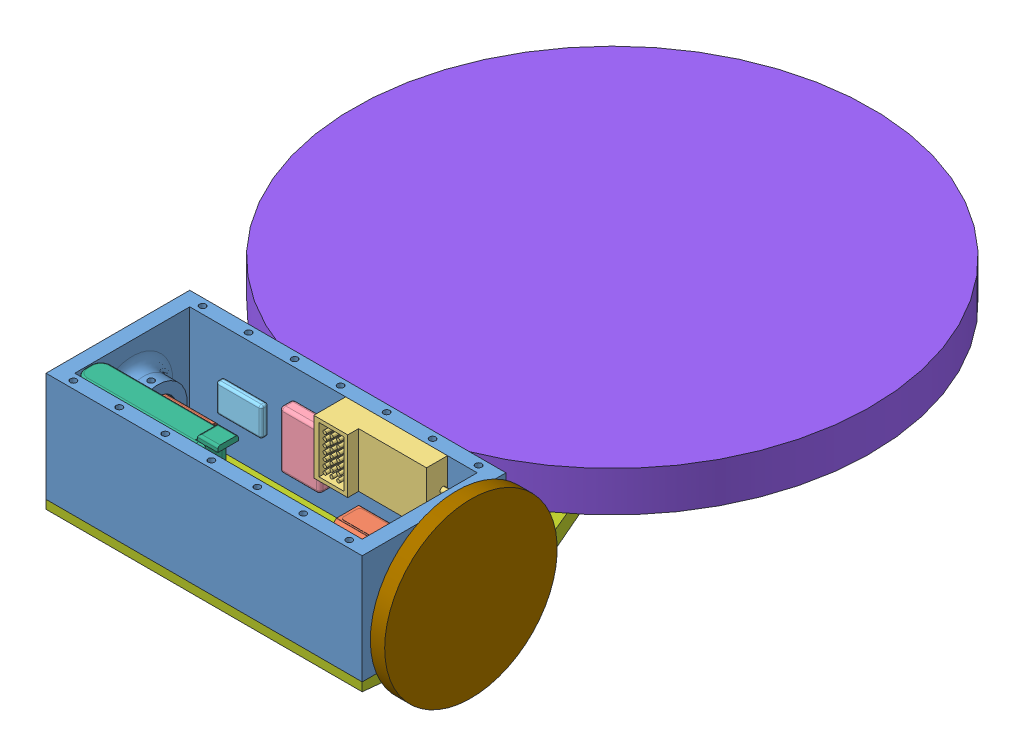
SolidWorks assembly tombstone chassis, configuration Default. Lengths in mm.
Overall size (238.32 80.48 307.99).
11 component instances, 9 part files, 21 mates.
Components (placement in the parent):
- mid chassis-1: mid chassis [Default] at (-76.5443 -11.5001 27.5648) size (144.78 48.26 63.5)
- Brushed Drive Motor-1: Brushed Drive Motor [Default] at (-65.1315 16.4399 -4.1852) x (1 0 0) z (0 -1 0) size (53.82 17.99 16.08)
- Brushed Drive Motor-2: Brushed Drive Motor [Default] at (51.7429 16.4399 -4.1852) x (-1 0 0) z (0 -1 0) size (53.82 17.99 16.08)
- Reciever (1)-1: Reciever (1) [Default] at (-1.286 16.5699 -29.5852) x (1 0 0) z (0 -1 0) size (54.3 14.1 24)
- Drive ESC-1: Drive ESC [Default] at (-24.552 28.461 -23.5852) x (1 0 0) z (0 1 0) size (17.78 6 25.4)
- Brushless Weapon ESC-1: Brushless Weapon ESC [Default] at (-55.4048 21.2789 -26.4102) x (1 0 0) z (0 1 0) size (20 3.17 12.7)
- Battery-1: Battery [Default] at (-70.1943 10.0699 9.7148) size (62 32.9 11.5)
- tombstone base-1: tombstone base [Default] at (-76.5443 40.5699 27.5648) size (139.7 8.89 206.76) (hidden)
- tombstone base-2: tombstone base [Default] at (63.1557 -7.6901 27.5648) x (-1 0 0) z (0 0 1) size (139.7 8.89 206.76)
- Spinner mock-1: Spinner mock [Default] at (-6.6943 11.8684 -152.7752) x (0.999056 0 0.043444) z (-0.043444 0 0.999056) size (228.6 17.78 228.6)
- 2.5 in wheel-1: 2.5 in wheel [Default] at (79.4451 16.4399 -4.1852) x (0 0.057857 0.998325) z (-1 0 0) size (76.2 76.2 6.35)
Mates (geometry in assembly coordinates):
- Concentric1: concentric aligned: cylinder of mid chassis-1 through (-86.9583 16.4399 -4.1852) axis (1 0 0) radius 8.255; cylinder of Brushed Drive Motor-1 through (-75.5043 16.4399 -4.1852) axis (1 0 0) radius 8
- Coincident1: coincident aligned: plane of mid chassis-1 through (-76.5443 -7.6901 27.5648) normal (-1 0 0); plane of Brushed Drive Motor-1 through (-76.5443 24.5763 -12.3217) normal (-1 0 0)
- Parallel1: parallel aligned: plane of mid chassis-1 through (-76.5443 40.5699 27.5648) normal (0 1 0); plane of Brushed Drive Motor-1 through (-63.1955 22.5399 0.0148) normal (0 1 0)
- Concentric2: concentric anti-aligned: cylinder of mid chassis-1 through (-86.9583 16.4399 -4.1852) axis (1 0 0) radius 8.255; cylinder of Brushed Drive Motor-2 through (62.1157 16.4399 -4.1852) axis (-1 0 0) radius 8
- Coincident2: coincident aligned: plane of mid chassis-1 through (63.1557 -7.6901 27.5648) normal (1 0 0); plane of Brushed Drive Motor-2 through (63.1557 24.5763 3.9513) normal (1 0 0)
- Parallel2: parallel aligned: plane of mid chassis-1 through (-76.5443 40.5699 27.5648) normal (0 1 0); plane of Brushed Drive Motor-2 through (49.8069 22.5399 -8.3852) normal (0 1 0)
- Coincident3: coincident anti-aligned: plane of mid chassis-1 through (-76.5443 40.5699 21.2148) normal (0 0 -1); plane of Battery-1 through (-70.1943 10.0699 21.2148) normal (0 0 1)
- Coincident4: coincident aligned: plane of mid chassis-1 through (-76.5443 40.5699 27.5648) normal (0 1 0); plane of Battery-1 through (-70.1943 40.5699 21.2148) normal (0 1 0)
- Coincident5: coincident anti-aligned: plane of mid chassis-1 through (-70.1943 40.5699 27.5648) normal (1 0 0); plane of Battery-1 through (-70.1943 10.0699 21.2148) normal (-1 0 0)
- Coincident6: coincident anti-aligned: plane of mid chassis-1 through (-76.5443 40.5699 -29.5852) normal (0 0 1); plane of Reciever (1)-1 through (-1.286 16.5699 -29.5852) normal (0 0 -1)
- Coincident7: coincident aligned: plane of mid chassis-1 through (-76.5443 40.5699 27.5648) normal (0 1 0); plane of Reciever (1)-1 through (-1.286 40.5699 -20.2852) normal (0 1 0)
- Coincident8: coincident anti-aligned: plane of mid chassis-1 through (-76.5443 40.5699 -29.5852) normal (0 0 1); plane of Drive ESC-1 through (-24.552 28.461 -29.5852) normal (0 0 -1)
- Coincident9: coincident anti-aligned: plane of mid chassis-1 through (-76.5443 40.5699 -29.5852) normal (0 0 1); plane of Brushless Weapon ESC-1 through (-55.4048 21.2789 -29.5852) normal (0 0 -1)
- Concentric3: concentric aligned: cylinder of mid chassis-1 through (-67.6543 -3.8801 -32.7602) axis (0 -1 0) radius 1.4; cylinder of tombstone base-2 through (-67.6543 -0.0701 -32.7602) axis (0 -1 0) radius 1.4
- Coincident13: coincident anti-aligned: plane of mid chassis-1 through (-76.5443 -7.6901 27.5648) normal (0 -1 0); plane of tombstone base-2 through (63.1557 -7.6901 27.5648) normal (0 1 0)
- Coincident16: coincident anti-aligned: plane of mid chassis-1 through (-76.5443 40.5699 27.5648) normal (0 1 0); plane of tombstone base-1 through (-76.5443 40.5699 27.5648) normal (0 -1 0)
- Parallel8: parallel aligned: plane of tombstone base-1 through (-99.0887 40.5699 18.1713) normal (-0.923077 0 -0.384615); plane of tombstone base-2 through (-78.423 -7.6901 -31.4263) normal (-0.923077 0 -0.384615)
- Coincident18: coincident aligned: plane of tombstone base-1 through (65.0344 40.5699 -31.4263) normal (0.923077 0 -0.384615); plane of tombstone base-2 through (85.7001 -7.6901 18.1713) normal (0.923077 0 -0.384615)
- Coincident19: coincident aligned: plane of mid chassis-1 through (-76.5443 -7.6901 27.5648) normal (0 0 1); plane of tombstone base-1 through (-76.5443 49.4599 27.5648) normal (0 0 1)
- Concentric11: concentric anti-aligned: cylinder of tombstone base-2 through (-6.6943 -5.1501 -152.7752) axis (0 -1 0) radius 2.5; circle of Spinner mock-1
- Concentric12: concentric anti-aligned: cylinder of mid chassis-1 through (65.6957 16.4399 -4.1852) axis (-1 0 0) radius 4.6745; cylinder of 2.5 in wheel-1 through (73.0951 16.4399 -4.1852) axis (1 0 0) radius 38.1
